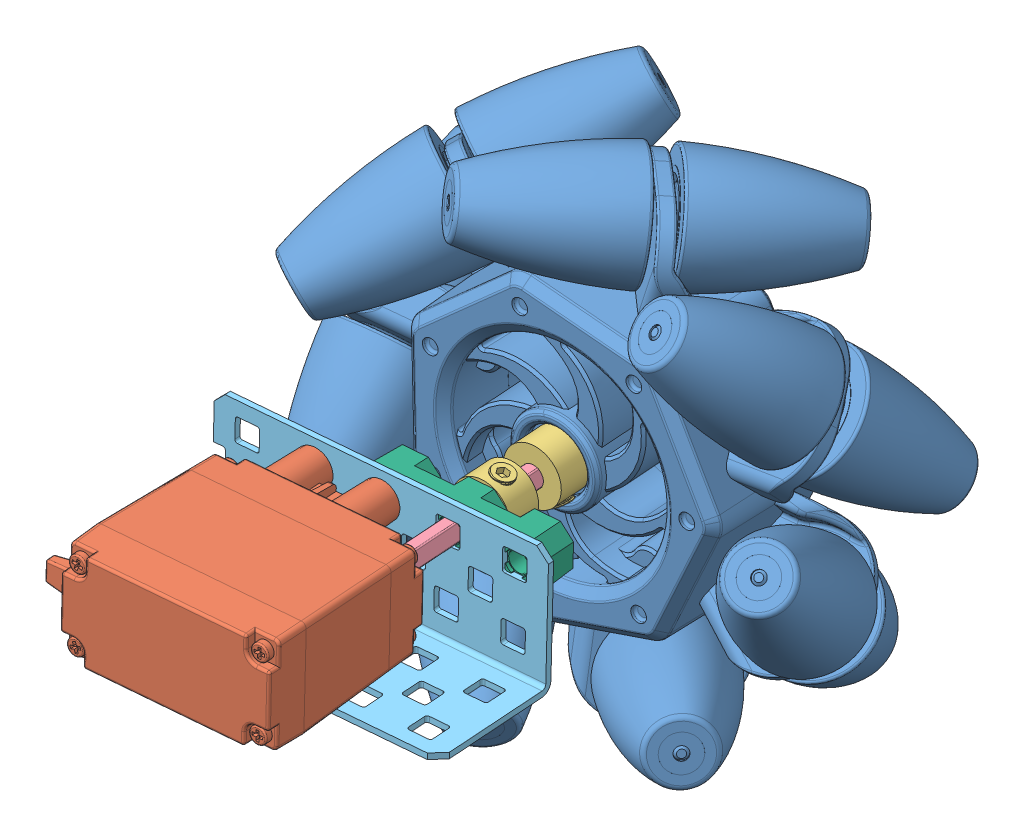
SolidWorks assembly wheel_motor_2, configuration Default. Lengths in mm.
Overall size (155.55 152.34 129.25).
8 component instances, 6 part files, 19 mates.
Components (placement in the parent):
- vex_mecanum_2-2: vex_mecanum_2 [Default] at (-318.3154 279.285 -60.6464) x (0.265563 -0.964094 -0.000007) z (-0.959833 -0.26439 0.093909) size (122.89 63 122.12)
- vex_motor269-1: vex_motor269 [Default] at (-322.0413 281.3713 21.0961) x (0.995892 -0.003261 -0.090486) z (0.090539 0.024932 0.995581) size (46.4 20 51.81)
- SHAFT-COLLAR-1: SHAFT-COLLAR [Default] at (-316.93 279.6666 -45.4121) x (-0.85266 -0.514581 0.090428) z (-0.090539 -0.024932 -0.995581) size (11 11.46 6.6)
- SHAFT-COLLAR-2: SHAFT-COLLAR [Default] at (-319.6827 278.9085 -75.6817) x (0.985086 -0.149117 -0.08585) z (0.090539 0.024932 0.995581) size (11 11.46 6.6)
- SHAFT-4000-1: SHAFT-4000 [Default] at (-317.6837 279.4564 -53.6811) x (-0.959833 -0.26439 0.093909) z (0.090539 0.024932 0.995581) size (4.18 4.18 76.3)
- SHAFT-COLLAR-5: SHAFT-COLLAR [Default] at (-315.864 279.9601 -33.6905) x (-0.967484 0.239272 0.081992) z (0.090539 0.024932 0.995581) size (11 11.46 6.6)
- angle-1: angle [Default] at (-351.4327 332.4234 -20.9012) x (0.995892 -0.003261 -0.090486) z (0.00099 0.999684 -0.025124) size (63.5 25.4 25.4)
- BEARING-FLAT-1: BEARING-FLAT [Default] at (-296.7351 265.2284 -114.7375) x (0.090539 0.024932 0.995581) z (-0.00099 -0.999684 0.025124) size (7.04 35.56 10.16)
Mates (geometry in assembly coordinates):
- Coincident7: coincident anti-aligned: plane of vex_mecanum_2-2 through (-317.2289 279.5842 -48.6995) normal (0.090539 0.024932 0.995581); plane of SHAFT-COLLAR-1 through (-317.2289 279.5842 -48.6995) normal (-0.090539 -0.024932 -0.995581)
- Concentric1: concentric aligned: cylinder of vex_mecanum_2-2 through (-317.0479 279.6341 -46.7083) axis (-0.090539 -0.024932 -0.995581) radius 6; cylinder of SHAFT-COLLAR-1 through (-316.631 279.7489 -42.1247) axis (-0.090539 -0.024932 -0.995581) radius 5.5
- Coincident8: coincident anti-aligned: plane of vex_mecanum_2-2 through (-319.3838 278.9909 -72.3943) normal (-0.090539 -0.024932 -0.995581); plane of SHAFT-COLLAR-2 through (-319.3838 278.9909 -72.3943) normal (0.090539 0.024932 0.995581)
- Concentric2: concentric aligned: circle of vex_mecanum_2-2; cylinder of SHAFT-COLLAR-2 through (-319.9817 278.8262 -78.9691) axis (0.090539 0.024932 0.995581) radius 5.5
- Distance2: distance = 0.04 mm: plane of SHAFT-4000-1 through (-311.139 279.6121 -3.2547) normal (0.265563 -0.964094 -0.000007); line of vex_mecanum_2-2 through (-318.1543 277.7218 -71.92) axis (0.090539 0.024932 0.995581)
- Distance3: distance = 0.04 mm: plane of SHAFT-4000-1 through (-315.0297 281.8337 -2.9565) normal (-0.959833 -0.26439 0.093909); line of vex_mecanum_2-2 through (-318.7125 278.3458 -50.8438) axis (-0.090539 -0.024932 -0.995581)
- Distance4: distance = 0.04 mm: plane of SHAFT-4000-1 through (-311.139 279.6121 -3.2547) normal (0.265563 -0.964094 -0.000007); line of vex_mecanum_2-2 through (-317.7934 277.821 -50.9142) axis (-0.090539 -0.024932 -0.995581)
- Coincident31: coincident aligned: plane of SHAFT-COLLAR-2 through (-319.9817 278.8262 -78.9691) normal (-0.090539 -0.024932 -0.995581); plane of SHAFT-4000-1 through (-317.8324 288.1415 -79.3979) normal (-0.090539 -0.024932 -0.995581)
- Coincident25: coincident anti-aligned: plane of vex_motor269-1 through (-311.0903 279.6256 -3.2595) normal (-0.265563 0.964094 0.000007); plane of SHAFT-4000-1 through (-311.139 279.6121 -3.2547) normal (0.265563 -0.964094 -0.000007)
- Coincident26: coincident anti-aligned: plane of vex_motor269-1 through (-315.0432 281.8827 -2.9565) normal (0.959833 0.26439 -0.093909); plane of SHAFT-4000-1 through (-315.0297 281.8337 -2.9565) normal (-0.959833 -0.26439 0.093909)
- Coincident27: coincident anti-aligned: plane of vex_motor269-1 through (-314.1865 278.7727 -2.9566) normal (-0.090539 -0.024932 -0.995581); plane of SHAFT-4000-1 through (-311.139 279.6121 -3.2547) normal (0.090539 0.024932 0.995581)
- Concentric3: concentric anti-aligned: cylinder of SHAFT-COLLAR-1 through (-316.631 279.7489 -42.1247) axis (-0.090539 -0.024932 -0.995581) radius 5.5; cylinder of SHAFT-COLLAR-5 through (-316.163 279.8778 -36.9779) axis (0.090539 0.024932 0.995581) radius 5.5
- Concentric4: concentric aligned: circle of vex_motor269-1; circle of angle-1
- Concentric5: concentric aligned: circle of vex_motor269-1; circle of angle-1
- Coincident28: coincident aligned: circle of vex_motor269-1; plane of angle-1 through (-612.0874 286.4111 3.9552) normal (0.090539 0.024932 0.995581)
- Coincident29: coincident anti-aligned: plane of angle-1 through (-612.1932 286.382 2.792) normal (-0.090539 -0.024932 -0.995581); plane of BEARING-FLAT-1 through (-332.6798 285.3689 -22.6019) normal (0.090539 0.024932 0.995581)
- Concentric6: concentric anti-aligned: circle of BEARING-FLAT-1; circle of angle-1
- Concentric7: concentric aligned: circle of BEARING-FLAT-1; circle of angle-1
- Coincident30: coincident anti-aligned: plane of SHAFT-COLLAR-5 through (-315.5651 280.0424 -30.4031) normal (0.090539 0.024932 0.995581); plane of BEARING-FLAT-1 through (-321.6145 286.0516 -30.0034) normal (-0.090539 -0.024932 -0.995581)
